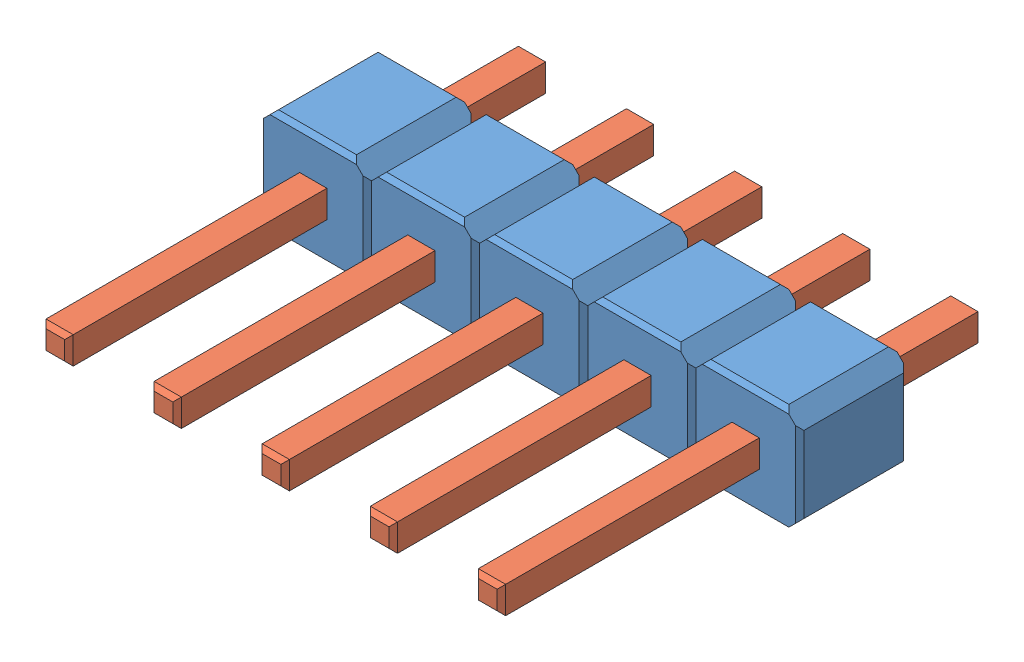
SolidWorks assembly pls_1x5_vert, configuration Default. Lengths in mm.
Overall size (12.7 2.5 11.3).
15 component instances, 2 part files, 8 mates.
Components (placement in the parent):
- pls_1_vert-1: pls_1_vert [Default] at (2.4589 -1.2488 -2.1291) size (2.54 2.5 11.3)
  - pin_plastic-1: pin_plastic [По умолчанию] at (1.6831 0.6372 -1.2507) size (2.54 2.5 2.54)
  - pin-1: pin [Default] at (-0.8569 0.6372 7.3493) x (1 0 0) z (0 1 0) size (0.64 11.3 0.64)
- pls_1_vert-2: pls_1_vert [Default] at (-0.0811 -1.2488 -2.1291) size (2.54 2.5 11.3)
  - pin_plastic-1: pin_plastic [По умолчанию] at (1.6831 0.6372 -1.2507) size (2.54 2.5 2.54)
  - pin-1: pin [Default] at (-0.8569 0.6372 7.3493) x (1 0 0) z (0 1 0) size (0.64 11.3 0.64)
- pls_1_vert-4: pls_1_vert [Default] at (-2.6211 -1.2488 -2.1291) size (2.54 2.5 11.3)
  - pin_plastic-1: pin_plastic [По умолчанию] at (1.6831 0.6372 -1.2507) size (2.54 2.5 2.54)
  - pin-1: pin [Default] at (-0.8569 0.6372 7.3493) x (1 0 0) z (0 1 0) size (0.64 11.3 0.64)
- pls_1_vert-5: pls_1_vert [Default] at (-5.1611 -1.2488 -2.1291) size (2.54 2.5 11.3)
  - pin_plastic-1: pin_plastic [По умолчанию] at (1.6831 0.6372 -1.2507) size (2.54 2.5 2.54)
  - pin-1: pin [Default] at (-0.8569 0.6372 7.3493) x (1 0 0) z (0 1 0) size (0.64 11.3 0.64)
- pls_1_vert-6: pls_1_vert [Default] at (-7.7011 -1.2488 -2.1291) size (2.54 2.5 11.3)
  - pin_plastic-1: pin_plastic [По умолчанию] at (1.6831 0.6372 -1.2507) size (2.54 2.5 2.54)
  - pin-1: pin [Default] at (-0.8569 0.6372 7.3493) x (1 0 0) z (0 1 0) size (0.64 11.3 0.64)
Mates (geometry in assembly coordinates):
- Совпадение1: coincident anti-aligned: line of pls_1_vert-1/pin_plastic-1 through (0.332 -1.5081 -0.9398) axis (0 1 0); line of pls_1_vert-2/pin_plastic-1 through (0.332 0.2848 -0.9398) axis (0 -1 0)
- Совпадение2: coincident aligned: line of pls_1_vert-1/pin_plastic-1 through (0.332 0.2848 -0.9398) axis (0 0 -1); line of pls_1_vert-2/pin_plastic-1 through (0.332 0.2848 -0.9398) axis (0 0 -1)
- Совпадение3: coincident: line of pls_1_vert-2/pin_plastic-1 through (-2.208 -1.5081 -0.9398) axis (0 1 0); line of pls_1_vert-4/pin_plastic-1 through (-2.208 0.2848 -0.9398) axis (0 -1 0)
- Совпадение4: coincident aligned: line of pls_1_vert-2/pin_plastic-1 through (-2.208 0.2848 -0.9398) axis (0 0 -1); line of pls_1_vert-4/pin_plastic-1 through (-2.208 0.2848 -0.9398) axis (0 0 -1)
- Совпадение5: coincident: line of pls_1_vert-4/pin_plastic-1 through (-4.748 -1.5081 -0.9398) axis (0 1 0); line of pls_1_vert-5/pin_plastic-1 through (-4.748 0.2848 -0.9398) axis (0 -1 0)
- Совпадение6: coincident aligned: line of pls_1_vert-4/pin_plastic-1 through (-4.748 0.2848 -0.9398) axis (0 0 -1); line of pls_1_vert-5/pin_plastic-1 through (-4.748 0.2848 -0.9398) axis (0 0 -1)
- Совпадение7: coincident: line of pls_1_vert-5/pin_plastic-1 through (-7.288 -1.5081 -0.9398) axis (0 1 0); line of pls_1_vert-6/pin_plastic-1 through (-7.288 0.2848 -0.9398) axis (0 -1 0)
- Совпадение8: coincident aligned: line of pls_1_vert-5/pin_plastic-1 through (-7.288 0.2848 -0.9398) axis (0 0 -1); line of pls_1_vert-6/pin_plastic-1 through (-7.288 0.2848 -0.9398) axis (0 0 -1)
